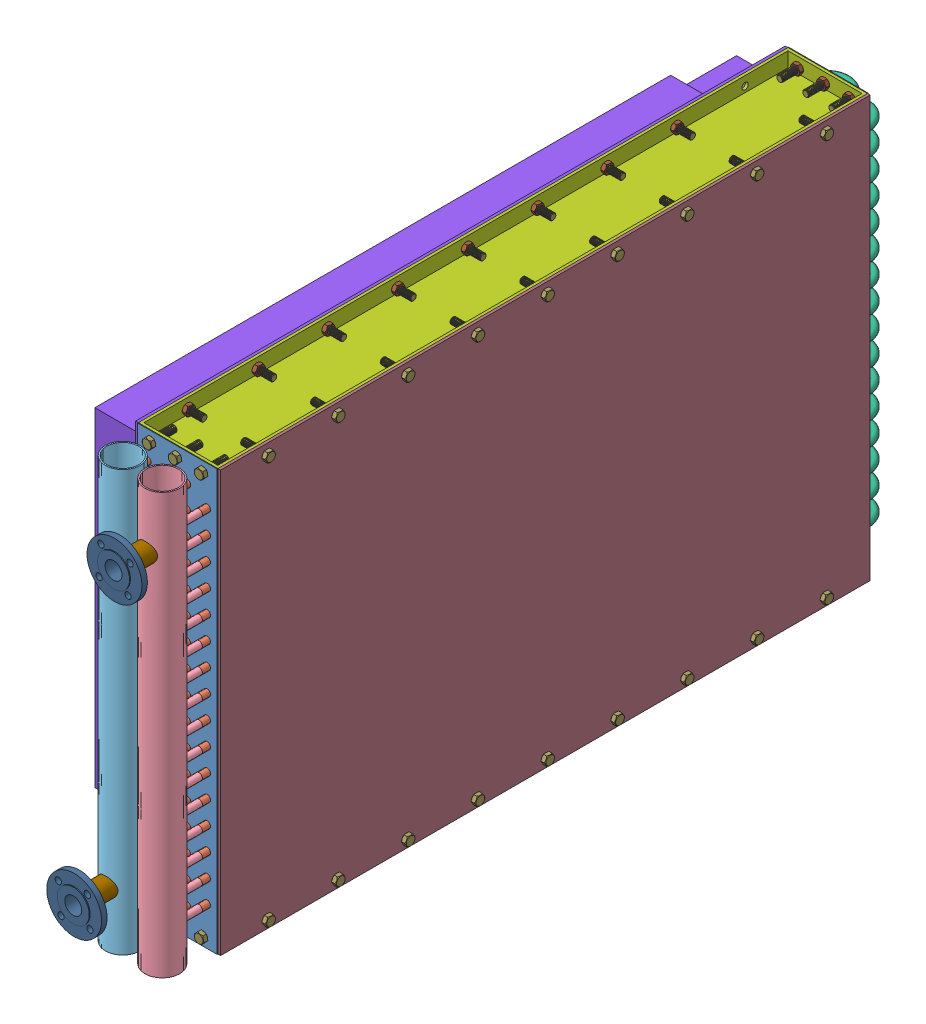
SolidWorks assembly Zagrijač zraka - assembly, configuration Default. Lengths in mm.
Overall size (396.33 920 1679.05).
277 component instances, 14 part files, 58 mates.
Components (placement in the parent):
- Početna i krajnja izmjenjivačka lamela - zagrijač zraka-2: Početna i krajnja izmjenjivačka lamela - zagrijač zraka [Default] at (252.8729 497.8938 741.12) size (173.9 920 1.5)
- Izmjenjivačka cijev - zagrijač zraka-2: Izmjenjivačka cijev - zagrijač zraka [Default] at (274.5217 897.8938 -699.63) x (0.942593 -0.333944 0) z (0 0 1) size (15 15 1460)
- Izmjenjivačka lamela - zagrijač zraka-2: Izmjenjivačka lamela - zagrijač zraka [Default] at (252.8729 497.8938 719.62) size (173.9 850 1.5)
- Izmjenjivačka lamela - zagrijač zraka-142: Izmjenjivačka lamela - zagrijač zraka [Default] at (252.8729 497.8938 699.62) size (173.9 850 1.5)
- Izmjenjivačka lamela - zagrijač zraka-143: Izmjenjivačka lamela - zagrijač zraka [Default] at (252.8729 497.8938 679.62) size (173.9 850 1.5)
- Izmjenjivačka lamela - zagrijač zraka-144: Izmjenjivačka lamela - zagrijač zraka [Default] at (252.8729 497.8938 659.62) size (173.9 850 1.5)
- Izmjenjivačka lamela - zagrijač zraka-145: Izmjenjivačka lamela - zagrijač zraka [Default] at (252.8729 497.8938 639.62) size (173.9 850 1.5)
- Izmjenjivačka lamela - zagrijač zraka-146: Izmjenjivačka lamela - zagrijač zraka [Default] at (252.8729 497.8938 619.62) size (173.9 850 1.5)
- Izmjenjivačka lamela - zagrijač zraka-147: Izmjenjivačka lamela - zagrijač zraka [Default] at (252.8729 497.8938 599.62) size (173.9 850 1.5)
- Izmjenjivačka lamela - zagrijač zraka-148: Izmjenjivačka lamela - zagrijač zraka [Default] at (252.8729 497.8938 579.62) size (173.9 850 1.5)
- Izmjenjivačka lamela - zagrijač zraka-149: Izmjenjivačka lamela - zagrijač zraka [Default] at (252.8729 497.8938 559.62) size (173.9 850 1.5)
- Izmjenjivačka lamela - zagrijač zraka-150: Izmjenjivačka lamela - zagrijač zraka [Default] at (252.8729 497.8938 539.62) size (173.9 850 1.5)
- Izmjenjivačka lamela - zagrijač zraka-151: Izmjenjivačka lamela - zagrijač zraka [Default] at (252.8729 497.8938 519.62) size (173.9 850 1.5)
- Izmjenjivačka lamela - zagrijač zraka-152: Izmjenjivačka lamela - zagrijač zraka [Default] at (252.8729 497.8938 499.62) size (173.9 850 1.5)
- Izmjenjivačka lamela - zagrijač zraka-153: Izmjenjivačka lamela - zagrijač zraka [Default] at (252.8729 497.8938 479.62) size (173.9 850 1.5)
- Izmjenjivačka lamela - zagrijač zraka-154: Izmjenjivačka lamela - zagrijač zraka [Default] at (252.8729 497.8938 459.62) size (173.9 850 1.5)
- Izmjenjivačka lamela - zagrijač zraka-155: Izmjenjivačka lamela - zagrijač zraka [Default] at (252.8729 497.8938 439.62) size (173.9 850 1.5)
- Izmjenjivačka lamela - zagrijač zraka-156: Izmjenjivačka lamela - zagrijač zraka [Default] at (252.8729 497.8938 419.62) size (173.9 850 1.5)
- Izmjenjivačka lamela - zagrijač zraka-157: Izmjenjivačka lamela - zagrijač zraka [Default] at (252.8729 497.8938 399.62) size (173.9 850 1.5)
- Izmjenjivačka lamela - zagrijač zraka-158: Izmjenjivačka lamela - zagrijač zraka [Default] at (252.8729 497.8938 379.62) size (173.9 850 1.5)
- Izmjenjivačka lamela - zagrijač zraka-159: Izmjenjivačka lamela - zagrijač zraka [Default] at (252.8729 497.8938 359.62) size (173.9 850 1.5)
- Izmjenjivačka lamela - zagrijač zraka-160: Izmjenjivačka lamela - zagrijač zraka [Default] at (252.8729 497.8938 339.62) size (173.9 850 1.5)
- Izmjenjivačka lamela - zagrijač zraka-161: Izmjenjivačka lamela - zagrijač zraka [Default] at (252.8729 497.8938 319.62) size (173.9 850 1.5)
- Izmjenjivačka lamela - zagrijač zraka-162: Izmjenjivačka lamela - zagrijač zraka [Default] at (252.8729 497.8938 299.62) size (173.9 850 1.5)
- Izmjenjivačka lamela - zagrijač zraka-163: Izmjenjivačka lamela - zagrijač zraka [Default] at (252.8729 497.8938 279.62) size (173.9 850 1.5)
- Izmjenjivačka lamela - zagrijač zraka-164: Izmjenjivačka lamela - zagrijač zraka [Default] at (252.8729 497.8938 259.62) size (173.9 850 1.5)
- Izmjenjivačka lamela - zagrijač zraka-165: Izmjenjivačka lamela - zagrijač zraka [Default] at (252.8729 497.8938 239.62) size (173.9 850 1.5)
- Izmjenjivačka lamela - zagrijač zraka-166: Izmjenjivačka lamela - zagrijač zraka [Default] at (252.8729 497.8938 219.62) size (173.9 850 1.5)
- Izmjenjivačka lamela - zagrijač zraka-167: Izmjenjivačka lamela - zagrijač zraka [Default] at (252.8729 497.8938 199.62) size (173.9 850 1.5)
- Izmjenjivačka lamela - zagrijač zraka-168: Izmjenjivačka lamela - zagrijač zraka [Default] at (252.8729 497.8938 179.62) size (173.9 850 1.5)
- Izmjenjivačka lamela - zagrijač zraka-169: Izmjenjivačka lamela - zagrijač zraka [Default] at (252.8729 497.8938 159.62) size (173.9 850 1.5)
- Izmjenjivačka lamela - zagrijač zraka-170: Izmjenjivačka lamela - zagrijač zraka [Default] at (252.8729 497.8938 139.62) size (173.9 850 1.5)
- Izmjenjivačka lamela - zagrijač zraka-171: Izmjenjivačka lamela - zagrijač zraka [Default] at (252.8729 497.8938 119.62) size (173.9 850 1.5)
- Izmjenjivačka lamela - zagrijač zraka-172: Izmjenjivačka lamela - zagrijač zraka [Default] at (252.8729 497.8938 99.62) size (173.9 850 1.5)
- Izmjenjivačka lamela - zagrijač zraka-173: Izmjenjivačka lamela - zagrijač zraka [Default] at (252.8729 497.8938 79.62) size (173.9 850 1.5)
- Izmjenjivačka lamela - zagrijač zraka-174: Izmjenjivačka lamela - zagrijač zraka [Default] at (252.8729 497.8938 59.62) size (173.9 850 1.5)
- Izmjenjivačka lamela - zagrijač zraka-175: Izmjenjivačka lamela - zagrijač zraka [Default] at (252.8729 497.8938 39.62) size (173.9 850 1.5)
- Izmjenjivačka lamela - zagrijač zraka-176: Izmjenjivačka lamela - zagrijač zraka [Default] at (252.8729 497.8938 19.62) size (173.9 850 1.5)
- Izmjenjivačka lamela - zagrijač zraka-177: Izmjenjivačka lamela - zagrijač zraka [Default] at (252.8729 497.8938 -0.38) size (173.9 850 1.5)
- Izmjenjivačka lamela - zagrijač zraka-178: Izmjenjivačka lamela - zagrijač zraka [Default] at (252.8729 497.8938 -20.38) size (173.9 850 1.5)
- Izmjenjivačka lamela - zagrijač zraka-179: Izmjenjivačka lamela - zagrijač zraka [Default] at (252.8729 497.8938 -40.38) size (173.9 850 1.5)
- Izmjenjivačka lamela - zagrijač zraka-180: Izmjenjivačka lamela - zagrijač zraka [Default] at (252.8729 497.8938 -60.38) size (173.9 850 1.5)
- Izmjenjivačka lamela - zagrijač zraka-181: Izmjenjivačka lamela - zagrijač zraka [Default] at (252.8729 497.8938 -80.38) size (173.9 850 1.5)
- Izmjenjivačka lamela - zagrijač zraka-182: Izmjenjivačka lamela - zagrijač zraka [Default] at (252.8729 497.8938 -100.38) size (173.9 850 1.5)
- Izmjenjivačka lamela - zagrijač zraka-183: Izmjenjivačka lamela - zagrijač zraka [Default] at (252.8729 497.8938 -120.38) size (173.9 850 1.5)
- Izmjenjivačka lamela - zagrijač zraka-184: Izmjenjivačka lamela - zagrijač zraka [Default] at (252.8729 497.8938 -140.38) size (173.9 850 1.5)
- Izmjenjivačka lamela - zagrijač zraka-185: Izmjenjivačka lamela - zagrijač zraka [Default] at (252.8729 497.8938 -160.38) size (173.9 850 1.5)
- Izmjenjivačka lamela - zagrijač zraka-186: Izmjenjivačka lamela - zagrijač zraka [Default] at (252.8729 497.8938 -180.38) size (173.9 850 1.5)
- Izmjenjivačka lamela - zagrijač zraka-187: Izmjenjivačka lamela - zagrijač zraka [Default] at (252.8729 497.8938 -200.38) size (173.9 850 1.5)
- Izmjenjivačka lamela - zagrijač zraka-188: Izmjenjivačka lamela - zagrijač zraka [Default] at (252.8729 497.8938 -220.38) size (173.9 850 1.5)
- Izmjenjivačka lamela - zagrijač zraka-189: Izmjenjivačka lamela - zagrijač zraka [Default] at (252.8729 497.8938 -240.38) size (173.9 850 1.5)
- Izmjenjivačka lamela - zagrijač zraka-190: Izmjenjivačka lamela - zagrijač zraka [Default] at (252.8729 497.8938 -260.38) size (173.9 850 1.5)
- Izmjenjivačka lamela - zagrijač zraka-191: Izmjenjivačka lamela - zagrijač zraka [Default] at (252.8729 497.8938 -280.38) size (173.9 850 1.5)
- Izmjenjivačka lamela - zagrijač zraka-192: Izmjenjivačka lamela - zagrijač zraka [Default] at (252.8729 497.8938 -300.38) size (173.9 850 1.5)
- Izmjenjivačka lamela - zagrijač zraka-193: Izmjenjivačka lamela - zagrijač zraka [Default] at (252.8729 497.8938 -320.38) size (173.9 850 1.5)
- Izmjenjivačka lamela - zagrijač zraka-194: Izmjenjivačka lamela - zagrijač zraka [Default] at (252.8729 497.8938 -340.38) size (173.9 850 1.5)
- Izmjenjivačka lamela - zagrijač zraka-195: Izmjenjivačka lamela - zagrijač zraka [Default] at (252.8729 497.8938 -360.38) size (173.9 850 1.5)
- Izmjenjivačka lamela - zagrijač zraka-196: Izmjenjivačka lamela - zagrijač zraka [Default] at (252.8729 497.8938 -380.38) size (173.9 850 1.5)
- Izmjenjivačka lamela - zagrijač zraka-197: Izmjenjivačka lamela - zagrijač zraka [Default] at (252.8729 497.8938 -400.38) size (173.9 850 1.5)
- Izmjenjivačka lamela - zagrijač zraka-198: Izmjenjivačka lamela - zagrijač zraka [Default] at (252.8729 497.8938 -420.38) size (173.9 850 1.5)
- Izmjenjivačka lamela - zagrijač zraka-199: Izmjenjivačka lamela - zagrijač zraka [Default] at (252.8729 497.8938 -440.38) size (173.9 850 1.5)
- Izmjenjivačka lamela - zagrijač zraka-200: Izmjenjivačka lamela - zagrijač zraka [Default] at (252.8729 497.8938 -460.38) size (173.9 850 1.5)
- Izmjenjivačka lamela - zagrijač zraka-201: Izmjenjivačka lamela - zagrijač zraka [Default] at (252.8729 497.8938 -480.38) size (173.9 850 1.5)
- Izmjenjivačka lamela - zagrijač zraka-202: Izmjenjivačka lamela - zagrijač zraka [Default] at (252.8729 497.8938 -500.38) size (173.9 850 1.5)
- Izmjenjivačka lamela - zagrijač zraka-203: Izmjenjivačka lamela - zagrijač zraka [Default] at (252.8729 497.8938 -520.38) size (173.9 850 1.5)
- Izmjenjivačka lamela - zagrijač zraka-204: Izmjenjivačka lamela - zagrijač zraka [Default] at (252.8729 497.8938 -540.38) size (173.9 850 1.5)
- Izmjenjivačka lamela - zagrijač zraka-205: Izmjenjivačka lamela - zagrijač zraka [Default] at (252.8729 497.8938 -560.38) size (173.9 850 1.5)
- Izmjenjivačka lamela - zagrijač zraka-206: Izmjenjivačka lamela - zagrijač zraka [Default] at (252.8729 497.8938 -580.38) size (173.9 850 1.5)
- Izmjenjivačka lamela - zagrijač zraka-207: Izmjenjivačka lamela - zagrijač zraka [Default] at (252.8729 497.8938 -600.38) size (173.9 850 1.5)
- Izmjenjivačka lamela - zagrijač zraka-208: Izmjenjivačka lamela - zagrijač zraka [Default] at (252.8729 497.8938 -620.38) size (173.9 850 1.5)
- Izmjenjivačka lamela - zagrijač zraka-209: Izmjenjivačka lamela - zagrijač zraka [Default] at (252.8729 497.8938 -640.38) size (173.9 850 1.5)
- Izmjenjivačka lamela - zagrijač zraka-210: Izmjenjivačka lamela - zagrijač zraka [Default] at (252.8729 497.8938 -660.38) size (173.9 850 1.5)
- Početna i krajnja izmjenjivačka lamela - zagrijač zraka-6: Početna i krajnja izmjenjivačka lamela - zagrijač zraka [Default] at (252.8729 497.8938 -681.88) size (173.9 920 1.5)
- Izmjenjivačka cijev - zagrijač zraka-3: Izmjenjivačka cijev - zagrijač zraka [Default] at (187.9217 897.8938 -699.63) x (0.942593 -0.333944 0) z (0 0 1) size (15 15 1460)
- Izmjenjivačka cijev - zagrijač zraka-4: Izmjenjivačka cijev - zagrijač zraka [Default] at (274.5217 847.8938 -699.63) x (0.942593 -0.333944 0) z (0 0 1) size (15 15 1460)
- Izmjenjivačka cijev - zagrijač zraka-5: Izmjenjivačka cijev - zagrijač zraka [Default] at (187.9217 847.8938 -699.63) x (0.942593 -0.333944 0) z (0 0 1) size (15 15 1460)
- Izmjenjivačka cijev - zagrijač zraka-6: Izmjenjivačka cijev - zagrijač zraka [Default] at (274.5217 797.8938 -699.63) x (0.942593 -0.333944 0) z (0 0 1) size (15 15 1460)
- Izmjenjivačka cijev - zagrijač zraka-7: Izmjenjivačka cijev - zagrijač zraka [Default] at (187.9217 797.8938 -699.63) x (0.942593 -0.333944 0) z (0 0 1) size (15 15 1460)
- Izmjenjivačka cijev - zagrijač zraka-8: Izmjenjivačka cijev - zagrijač zraka [Default] at (274.5217 747.8938 -699.63) x (0.942593 -0.333944 0) z (0 0 1) size (15 15 1460)
- Izmjenjivačka cijev - zagrijač zraka-9: Izmjenjivačka cijev - zagrijač zraka [Default] at (187.9217 747.8938 -699.63) x (0.942593 -0.333944 0) z (0 0 1) size (15 15 1460)
- Izmjenjivačka cijev - zagrijač zraka-10: Izmjenjivačka cijev - zagrijač zraka [Default] at (274.5217 697.8938 -699.63) x (0.942593 -0.333944 0) z (0 0 1) size (15 15 1460)
- Izmjenjivačka cijev - zagrijač zraka-11: Izmjenjivačka cijev - zagrijač zraka [Default] at (187.9217 697.8938 -699.63) x (0.942593 -0.333944 0) z (0 0 1) size (15 15 1460)
- Izmjenjivačka cijev - zagrijač zraka-12: Izmjenjivačka cijev - zagrijač zraka [Default] at (274.5217 647.8938 -699.63) x (0.942593 -0.333944 0) z (0 0 1) size (15 15 1460)
- Izmjenjivačka cijev - zagrijač zraka-13: Izmjenjivačka cijev - zagrijač zraka [Default] at (187.9217 647.8938 -699.63) x (0.942593 -0.333944 0) z (0 0 1) size (15 15 1460)
- Izmjenjivačka cijev - zagrijač zraka-14: Izmjenjivačka cijev - zagrijač zraka [Default] at (274.5217 597.8938 -699.63) x (0.942593 -0.333944 0) z (0 0 1) size (15 15 1460)
- Izmjenjivačka cijev - zagrijač zraka-15: Izmjenjivačka cijev - zagrijač zraka [Default] at (187.9217 597.8938 -699.63) x (0.942593 -0.333944 0) z (0 0 1) size (15 15 1460)
- Izmjenjivačka cijev - zagrijač zraka-16: Izmjenjivačka cijev - zagrijač zraka [Default] at (274.5217 547.8938 -699.63) x (0.942593 -0.333944 0) z (0 0 1) size (15 15 1460)
- Izmjenjivačka cijev - zagrijač zraka-17: Izmjenjivačka cijev - zagrijač zraka [Default] at (187.9217 547.8938 -699.63) x (0.942593 -0.333944 0) z (0 0 1) size (15 15 1460)
- Izmjenjivačka cijev - zagrijač zraka-18: Izmjenjivačka cijev - zagrijač zraka [Default] at (274.5217 497.8938 -699.63) x (0.942593 -0.333944 0) z (0 0 1) size (15 15 1460)
- Izmjenjivačka cijev - zagrijač zraka-19: Izmjenjivačka cijev - zagrijač zraka [Default] at (187.9217 497.8938 -699.63) x (0.942593 -0.333944 0) z (0 0 1) size (15 15 1460)
- Izmjenjivačka cijev - zagrijač zraka-20: Izmjenjivačka cijev - zagrijač zraka [Default] at (274.5217 447.8938 -699.63) x (0.942593 -0.333944 0) z (0 0 1) size (15 15 1460)
- Izmjenjivačka cijev - zagrijač zraka-21: Izmjenjivačka cijev - zagrijač zraka [Default] at (187.9217 447.8938 -699.63) x (0.942593 -0.333944 0) z (0 0 1) size (15 15 1460)
- Izmjenjivačka cijev - zagrijač zraka-22: Izmjenjivačka cijev - zagrijač zraka [Default] at (274.5217 397.8938 -699.63) x (0.942593 -0.333944 0) z (0 0 1) size (15 15 1460)
- Izmjenjivačka cijev - zagrijač zraka-23: Izmjenjivačka cijev - zagrijač zraka [Default] at (187.9217 397.8938 -699.63) x (0.942593 -0.333944 0) z (0 0 1) size (15 15 1460)
- Izmjenjivačka cijev - zagrijač zraka-24: Izmjenjivačka cijev - zagrijač zraka [Default] at (274.5217 347.8938 -699.63) x (0.942593 -0.333944 0) z (0 0 1) size (15 15 1460)
- Izmjenjivačka cijev - zagrijač zraka-25: Izmjenjivačka cijev - zagrijač zraka [Default] at (187.9217 347.8938 -699.63) x (0.942593 -0.333944 0) z (0 0 1) size (15 15 1460)
- Izmjenjivačka cijev - zagrijač zraka-26: Izmjenjivačka cijev - zagrijač zraka [Default] at (274.5217 297.8938 -699.63) x (0.942593 -0.333944 0) z (0 0 1) size (15 15 1460)
- Izmjenjivačka cijev - zagrijač zraka-27: Izmjenjivačka cijev - zagrijač zraka [Default] at (187.9217 297.8938 -699.63) x (0.942593 -0.333944 0) z (0 0 1) size (15 15 1460)
- Izmjenjivačka cijev - zagrijač zraka-28: Izmjenjivačka cijev - zagrijač zraka [Default] at (274.5217 247.8938 -699.63) x (0.942593 -0.333944 0) z (0 0 1) size (15 15 1460)
- Izmjenjivačka cijev - zagrijač zraka-29: Izmjenjivačka cijev - zagrijač zraka [Default] at (187.9217 247.8938 -699.63) x (0.942593 -0.333944 0) z (0 0 1) size (15 15 1460)
- Izmjenjivačka cijev - zagrijač zraka-30: Izmjenjivačka cijev - zagrijač zraka [Default] at (274.5217 197.8938 -699.63) x (0.942593 -0.333944 0) z (0 0 1) size (15 15 1460)
- Izmjenjivačka cijev - zagrijač zraka-31: Izmjenjivačka cijev - zagrijač zraka [Default] at (187.9217 197.8938 -699.63) x (0.942593 -0.333944 0) z (0 0 1) size (15 15 1460)
- Izmjenjivačka cijev - zagrijač zraka-32: Izmjenjivačka cijev - zagrijač zraka [Default] at (274.5217 147.8938 -699.63) x (0.942593 -0.333944 0) z (0 0 1) size (15 15 1460)
- Izmjenjivačka cijev - zagrijač zraka-33: Izmjenjivačka cijev - zagrijač zraka [Default] at (187.9217 147.8938 -699.63) x (0.942593 -0.333944 0) z (0 0 1) size (15 15 1460)
- Izmjenjivačka cijev - zagrijač zraka-34: Izmjenjivačka cijev - zagrijač zraka [Default] at (274.5217 97.8938 -699.63) x (0.942593 -0.333944 0) z (0 0 1) size (15 15 1460)
- Izmjenjivačka cijev - zagrijač zraka-35: Izmjenjivačka cijev - zagrijač zraka [Default] at (187.9217 97.8938 -699.63) x (0.942593 -0.333944 0) z (0 0 1) size (15 15 1460)
- Izmjenjivačka cijev - zagrijač zraka-36: Izmjenjivačka cijev - zagrijač zraka [Default] at (317.8229 872.8938 -699.63) size (15 15 1460)
- Izmjenjivačka cijev - zagrijač zraka-37: Izmjenjivačka cijev - zagrijač zraka [Default] at (317.8229 822.8938 -699.63) size (15 15 1460)
- Izmjenjivačka cijev - zagrijač zraka-38: Izmjenjivačka cijev - zagrijač zraka [Default] at (317.8229 772.8938 -699.63) size (15 15 1460)
- Izmjenjivačka cijev - zagrijač zraka-39: Izmjenjivačka cijev - zagrijač zraka [Default] at (317.8229 722.8938 -699.63) size (15 15 1460)
- Izmjenjivačka cijev - zagrijač zraka-40: Izmjenjivačka cijev - zagrijač zraka [Default] at (317.8229 672.8938 -699.63) size (15 15 1460)
- Izmjenjivačka cijev - zagrijač zraka-41: Izmjenjivačka cijev - zagrijač zraka [Default] at (317.8229 622.8938 -699.63) size (15 15 1460)
- Izmjenjivačka cijev - zagrijač zraka-42: Izmjenjivačka cijev - zagrijač zraka [Default] at (317.8229 572.8938 -699.63) size (15 15 1460)
- Izmjenjivačka cijev - zagrijač zraka-43: Izmjenjivačka cijev - zagrijač zraka [Default] at (317.8229 522.8938 -699.63) size (15 15 1460)
- Izmjenjivačka cijev - zagrijač zraka-44: Izmjenjivačka cijev - zagrijač zraka [Default] at (317.8229 472.8938 -699.63) size (15 15 1460)
- Izmjenjivačka cijev - zagrijač zraka-45: Izmjenjivačka cijev - zagrijač zraka [Default] at (317.8229 422.8938 -699.63) size (15 15 1460)
- Izmjenjivačka cijev - zagrijač zraka-46: Izmjenjivačka cijev - zagrijač zraka [Default] at (317.8229 372.8938 -699.63) size (15 15 1460)
- Izmjenjivačka cijev - zagrijač zraka-47: Izmjenjivačka cijev - zagrijač zraka [Default] at (317.8229 322.8938 -699.63) size (15 15 1460)
- Izmjenjivačka cijev - zagrijač zraka-48: Izmjenjivačka cijev - zagrijač zraka [Default] at (317.8229 272.8938 -699.63) size (15 15 1460)
- Izmjenjivačka cijev - zagrijač zraka-49: Izmjenjivačka cijev - zagrijač zraka [Default] at (317.8229 222.8938 -699.63) size (15 15 1460)
- Izmjenjivačka cijev - zagrijač zraka-50: Izmjenjivačka cijev - zagrijač zraka [Default] at (317.8229 172.8938 -699.63) size (15 15 1460)
- Izmjenjivačka cijev - zagrijač zraka-51: Izmjenjivačka cijev - zagrijač zraka [Default] at (317.8229 122.8938 -699.63) size (15 15 1460)
- Izmjenjivačka cijev - zagrijač zraka-52: Izmjenjivačka cijev - zagrijač zraka [Default] at (231.2229 872.8938 -699.63) size (15 15 1460)
- Izmjenjivačka cijev - zagrijač zraka-53: Izmjenjivačka cijev - zagrijač zraka [Default] at (231.2229 822.8938 -699.63) size (15 15 1460)
- Izmjenjivačka cijev - zagrijač zraka-54: Izmjenjivačka cijev - zagrijač zraka [Default] at (231.2229 772.8938 -699.63) size (15 15 1460)
- Izmjenjivačka cijev - zagrijač zraka-55: Izmjenjivačka cijev - zagrijač zraka [Default] at (231.2229 722.8938 -699.63) size (15 15 1460)
- Izmjenjivačka cijev - zagrijač zraka-56: Izmjenjivačka cijev - zagrijač zraka [Default] at (231.2229 672.8938 -699.63) size (15 15 1460)
- Izmjenjivačka cijev - zagrijač zraka-57: Izmjenjivačka cijev - zagrijač zraka [Default] at (231.2229 622.8938 -699.63) size (15 15 1460)
- Izmjenjivačka cijev - zagrijač zraka-58: Izmjenjivačka cijev - zagrijač zraka [Default] at (231.2229 572.8938 -699.63) size (15 15 1460)
- Izmjenjivačka cijev - zagrijač zraka-59: Izmjenjivačka cijev - zagrijač zraka [Default] at (231.2229 522.8938 -699.63) size (15 15 1460)
- Izmjenjivačka cijev - zagrijač zraka-60: Izmjenjivačka cijev - zagrijač zraka [Default] at (231.2229 472.8938 -699.63) size (15 15 1460)
- Izmjenjivačka cijev - zagrijač zraka-61: Izmjenjivačka cijev - zagrijač zraka [Default] at (231.2229 422.8938 -699.63) size (15 15 1460)
- Izmjenjivačka cijev - zagrijač zraka-62: Izmjenjivačka cijev - zagrijač zraka [Default] at (231.2229 372.8938 -699.63) size (15 15 1460)
- Izmjenjivačka cijev - zagrijač zraka-63: Izmjenjivačka cijev - zagrijač zraka [Default] at (231.2229 322.8938 -699.63) size (15 15 1460)
- Izmjenjivačka cijev - zagrijač zraka-64: Izmjenjivačka cijev - zagrijač zraka [Default] at (231.2229 272.8938 -699.63) size (15 15 1460)
- Izmjenjivačka cijev - zagrijač zraka-65: Izmjenjivačka cijev - zagrijač zraka [Default] at (231.2229 222.8938 -699.63) size (15 15 1460)
- Izmjenjivačka cijev - zagrijač zraka-66: Izmjenjivačka cijev - zagrijač zraka [Default] at (231.2229 172.8938 -699.63) size (15 15 1460)
- Izmjenjivačka cijev - zagrijač zraka-67: Izmjenjivačka cijev - zagrijač zraka [Default] at (231.2229 122.8938 -699.63) size (15 15 1460)
- Ulazni kolektor - zagrijač zraka-1: Ulazni kolektor - zagrijač zraka [Default] at (297.5717 37.8938 820.37) x (-1 0 0) z (0 0 -1) size (76.1 920 98.05)
- Izlazni kolektor - zagrijač zraka-1: Izlazni kolektor - zagrijač zraka [Default] at (210.9717 37.8938 820.3712) x (-1 0 0) z (0 0 -1) size (76.1 920 98.05)
- U-spojnica - zagrijač zraka-1: U-spojnica - zagrijač zraka [Default] at (187.9217 897.8938 -699.63) x (1 0 0) z (0 1 0) size (101.6 50.8 15)
- U-spojnica - zagrijač zraka-2: U-spojnica - zagrijač zraka [Default] at (187.9217 847.8938 -699.63) x (1 0 0) z (0 1 0) size (101.6 50.8 15)
- U-spojnica - zagrijač zraka-3: U-spojnica - zagrijač zraka [Default] at (187.9217 797.8938 -699.63) x (1 0 0) z (0 1 0) size (101.6 50.8 15)
- U-spojnica - zagrijač zraka-4: U-spojnica - zagrijač zraka [Default] at (187.9217 747.8938 -699.63) x (1 0 0) z (0 1 0) size (101.6 50.8 15)
- U-spojnica - zagrijač zraka-5: U-spojnica - zagrijač zraka [Default] at (187.9217 697.8938 -699.63) x (1 0 0) z (0 1 0) size (101.6 50.8 15)
- U-spojnica - zagrijač zraka-6: U-spojnica - zagrijač zraka [Default] at (187.9217 647.8938 -699.63) x (1 0 0) z (0 1 0) size (101.6 50.8 15)
- U-spojnica - zagrijač zraka-7: U-spojnica - zagrijač zraka [Default] at (187.9217 597.8938 -699.63) x (1 0 0) z (0 1 0) size (101.6 50.8 15)
- U-spojnica - zagrijač zraka-8: U-spojnica - zagrijač zraka [Default] at (187.9217 547.8938 -699.63) x (1 0 0) z (0 1 0) size (101.6 50.8 15)
- U-spojnica - zagrijač zraka-9: U-spojnica - zagrijač zraka [Default] at (187.9217 497.8938 -699.63) x (1 0 0) z (0 1 0) size (101.6 50.8 15)
- U-spojnica - zagrijač zraka-10: U-spojnica - zagrijač zraka [Default] at (187.9217 447.8938 -699.63) x (1 0 0) z (0 1 0) size (101.6 50.8 15)
- U-spojnica - zagrijač zraka-11: U-spojnica - zagrijač zraka [Default] at (187.9217 397.8938 -699.63) x (1 0 0) z (0 1 0) size (101.6 50.8 15)
- U-spojnica - zagrijač zraka-12: U-spojnica - zagrijač zraka [Default] at (187.9217 347.8938 -699.63) x (1 0 0) z (0 1 0) size (101.6 50.8 15)
- U-spojnica - zagrijač zraka-13: U-spojnica - zagrijač zraka [Default] at (187.9217 297.8938 -699.63) x (1 0 0) z (0 1 0) size (101.6 50.8 15)
- U-spojnica - zagrijač zraka-14: U-spojnica - zagrijač zraka [Default] at (187.9217 247.8938 -699.63) x (1 0 0) z (0 1 0) size (101.6 50.8 15)
- U-spojnica - zagrijač zraka-15: U-spojnica - zagrijač zraka [Default] at (187.9217 197.8938 -699.63) x (1 0 0) z (0 1 0) size (101.6 50.8 15)
- U-spojnica - zagrijač zraka-16: U-spojnica - zagrijač zraka [Default] at (187.9217 147.8938 -699.63) x (1 0 0) z (0 1 0) size (101.6 50.8 15)
- U-spojnica - zagrijač zraka-17: U-spojnica - zagrijač zraka [Default] at (187.9217 97.8938 -699.63) x (1 0 0) z (0 1 0) size (101.6 50.8 15)
- U-spojnica - zagrijač zraka-18: U-spojnica - zagrijač zraka [Default] at (231.2229 872.8938 -699.63) x (1 0 0) z (0 1 0) size (101.6 50.8 15)
- U-spojnica - zagrijač zraka-19: U-spojnica - zagrijač zraka [Default] at (231.2229 822.8938 -699.63) x (1 0 0) z (0 1 0) size (101.6 50.8 15)
- U-spojnica - zagrijač zraka-20: U-spojnica - zagrijač zraka [Default] at (231.2229 772.8938 -699.63) x (1 0 0) z (0 1 0) size (101.6 50.8 15)
- U-spojnica - zagrijač zraka-21: U-spojnica - zagrijač zraka [Default] at (231.2229 722.8938 -699.63) x (1 0 0) z (0 1 0) size (101.6 50.8 15)
- U-spojnica - zagrijač zraka-22: U-spojnica - zagrijač zraka [Default] at (231.2229 672.8938 -699.63) x (1 0 0) z (0 1 0) size (101.6 50.8 15)
- U-spojnica - zagrijač zraka-23: U-spojnica - zagrijač zraka [Default] at (231.2229 622.8938 -699.63) x (1 0 0) z (0 1 0) size (101.6 50.8 15)
- U-spojnica - zagrijač zraka-24: U-spojnica - zagrijač zraka [Default] at (231.2229 572.8938 -699.63) x (1 0 0) z (0 1 0) size (101.6 50.8 15)
- U-spojnica - zagrijač zraka-25: U-spojnica - zagrijač zraka [Default] at (231.2229 522.8938 -699.63) x (1 0 0) z (0 1 0) size (101.6 50.8 15)
- U-spojnica - zagrijač zraka-26: U-spojnica - zagrijač zraka [Default] at (231.2229 472.8938 -699.63) x (1 0 0) z (0 1 0) size (101.6 50.8 15)
- U-spojnica - zagrijač zraka-27: U-spojnica - zagrijač zraka [Default] at (231.2229 422.8938 -699.63) x (1 0 0) z (0 1 0) size (101.6 50.8 15)
- U-spojnica - zagrijač zraka-28: U-spojnica - zagrijač zraka [Default] at (231.2229 372.8938 -699.63) x (1 0 0) z (0 1 0) size (101.6 50.8 15)
- U-spojnica - zagrijač zraka-29: U-spojnica - zagrijač zraka [Default] at (231.2229 322.8938 -699.63) x (1 0 0) z (0 1 0) size (101.6 50.8 15)
- U-spojnica - zagrijač zraka-30: U-spojnica - zagrijač zraka [Default] at (231.2229 272.8938 -699.63) x (1 0 0) z (0 1 0) size (101.6 50.8 15)
- U-spojnica - zagrijač zraka-31: U-spojnica - zagrijač zraka [Default] at (231.2229 222.8938 -699.63) x (1 0 0) z (0 1 0) size (101.6 50.8 15)
- U-spojnica - zagrijač zraka-32: U-spojnica - zagrijač zraka [Default] at (231.2229 172.8938 -699.63) x (1 0 0) z (0 1 0) size (101.6 50.8 15)
- U-spojnica - zagrijač zraka-33: U-spojnica - zagrijač zraka [Default] at (231.2229 122.8938 -699.63) x (1 0 0) z (0 1 0) size (101.6 50.8 15)
- Pokrovna stijenka - zagrijač zraka-1: Pokrovna stijenka - zagrijač zraka [Default] at (252.8729 957.8938 30.37) x (0 0 1) z (1 0 0) size (1421.5 35 173.9)
- Pokrovna stijenka - zagrijač zraka-2: Pokrovna stijenka - zagrijač zraka [Default] at (252.8729 37.8938 30.37) x (0 0 -1) z (1 0 0) size (1421.5 35 173.9)
- Kućište sa ventilatorom - zagrijač zraka-1: Kućište sa ventilatorom - zagrijač zraka [Default] at (165.9229 497.8938 30.37) x (0 0 -1) z (-1 0 0) size (1470.75 920 180)
- Priključna cijev - zagrijač zraka-1: Priključna cijev - zagrijač zraka [Default] at (297.5717 836.6938 832.0365) size (42.4 42.4 60)
- Priključna cijev - zagrijač zraka-2: Priključna cijev - zagrijač zraka [Default] at (210.9717 159.0938 833.6194) size (42.4 42.4 60)
- Prirubnica - zagrijač zraka-1: Prirubnica - zagrijač zraka [Default] at (297.5717 836.6938 927.0365) x (0.660561 -0.750772 0) z (0.750772 0.660561 0) size (120 35 120)
- Prirubnica - zagrijač zraka-2: Prirubnica - zagrijač zraka [Default] at (210.9717 159.0938 928.6194) x (0.769626 -0.638495 0) z (0.638495 0.769626 0) size (120 35 120)
- Matica - zagrijač zraka-1: Matica - zagrijač zraka [Default] at (309.8229 57.8938 726.12) size (25.38 22.75 9.17)
- Vijak - zagrijač zraka-1: Vijak - zagrijač zraka [Default] at (309.8229 57.8938 753.12) x (-0.684186 -0.729307 0) z (0 0 -1) size (25.4 22.36 60.5)
- Matica - zagrijač zraka-2: Matica - zagrijač zraka [Default] at (309.8229 937.8938 726.12) size (25.38 22.75 9.17)
- Matica - zagrijač zraka-3: Matica - zagrijač zraka [Default] at (252.8729 57.8938 726.12) size (25.38 22.75 9.17)
- Matica - zagrijač zraka-4: Matica - zagrijač zraka [Default] at (252.8729 937.8938 726.12) size (25.38 22.75 9.17)
- Matica - zagrijač zraka-5: Matica - zagrijač zraka [Default] at (195.9229 57.8938 726.12) size (25.38 22.75 9.17)
- Matica - zagrijač zraka-6: Matica - zagrijač zraka [Default] at (195.9229 937.8938 726.12) size (25.38 22.75 9.17)
- Vijak - zagrijač zraka-2: Vijak - zagrijač zraka [Default] at (309.8229 937.8938 753.12) x (-0.684186 -0.729307 0) z (0 0 -1) size (25.4 22.36 60.5)
- Vijak - zagrijač zraka-3: Vijak - zagrijač zraka [Default] at (252.8729 57.8938 753.12) x (-0.684186 -0.729307 0) z (0 0 -1) size (25.4 22.36 60.5)
- Vijak - zagrijač zraka-4: Vijak - zagrijač zraka [Default] at (252.8729 937.8938 753.12) x (-0.684186 -0.729307 0) z (0 0 -1) size (25.4 22.36 60.5)
- Vijak - zagrijač zraka-5: Vijak - zagrijač zraka [Default] at (195.9229 57.8938 753.12) x (-0.684186 -0.729307 0) z (0 0 -1) size (25.4 22.36 60.5)
- Vijak - zagrijač zraka-6: Vijak - zagrijač zraka [Default] at (195.9229 937.8938 753.12) x (-0.684186 -0.729307 0) z (0 0 -1) size (25.4 22.36 60.5)
- Zadnja strana - zagrijač zraka-1: Zadnja strana - zagrijač zraka [Default] at (339.8229 497.8938 30.37) x (0 0 -1) z (1 0 0) size (1421.5 920 6)
- Matica - zagrijač zraka-7: Matica - zagrijač zraka [Default] at (324.8229 57.8938 641.12) x (0 0 -1) z (1 0 0) size (25.38 22.75 9.17)
- Vijak - zagrijač zraka-7: Vijak - zagrijač zraka [Default] at (356.3229 57.8938 641.12) x (0 0 1) z (-1 0 0) size (25.4 22.36 60.5)
- Matica - zagrijač zraka-8: Matica - zagrijač zraka [Default] at (324.8229 937.8938 641.12) x (0 0 -1) z (1 0 0) size (25.38 22.75 9.17)
- Matica - zagrijač zraka-9: Matica - zagrijač zraka [Default] at (324.8229 57.8938 488.4325) x (0 0 -1) z (1 0 0) size (25.38 22.75 9.17)
- Matica - zagrijač zraka-10: Matica - zagrijač zraka [Default] at (324.8229 937.8938 488.4325) x (0 0 -1) z (1 0 0) size (25.38 22.75 9.17)
- Matica - zagrijač zraka-11: Matica - zagrijač zraka [Default] at (324.8229 57.8938 335.745) x (0 0 -1) z (1 0 0) size (25.38 22.75 9.17)
- Matica - zagrijač zraka-12: Matica - zagrijač zraka [Default] at (324.8229 937.8938 335.745) x (0 0 -1) z (1 0 0) size (25.38 22.75 9.17)
- Matica - zagrijač zraka-13: Matica - zagrijač zraka [Default] at (324.8229 57.8938 183.0575) x (0 0 -1) z (1 0 0) size (25.38 22.75 9.17)
- Matica - zagrijač zraka-14: Matica - zagrijač zraka [Default] at (324.8229 937.8938 183.0575) x (0 0 -1) z (1 0 0) size (25.38 22.75 9.17)
- Matica - zagrijač zraka-15: Matica - zagrijač zraka [Default] at (324.8229 57.8938 30.37) x (0 0 -1) z (1 0 0) size (25.38 22.75 9.17)
- Matica - zagrijač zraka-16: Matica - zagrijač zraka [Default] at (324.8229 937.8938 30.37) x (0 0 -1) z (1 0 0) size (25.38 22.75 9.17)
- Matica - zagrijač zraka-17: Matica - zagrijač zraka [Default] at (324.8229 57.8938 -122.3175) x (0 0 -1) z (1 0 0) size (25.38 22.75 9.17)
- Matica - zagrijač zraka-18: Matica - zagrijač zraka [Default] at (324.8229 937.8938 -122.3175) x (0 0 -1) z (1 0 0) size (25.38 22.75 9.17)
- Matica - zagrijač zraka-19: Matica - zagrijač zraka [Default] at (324.8229 57.8938 -275.005) x (0 0 -1) z (1 0 0) size (25.38 22.75 9.17)
- Matica - zagrijač zraka-20: Matica - zagrijač zraka [Default] at (324.8229 937.8938 -275.005) x (0 0 -1) z (1 0 0) size (25.38 22.75 9.17)
- Matica - zagrijač zraka-21: Matica - zagrijač zraka [Default] at (324.8229 57.8938 -427.6925) x (0 0 -1) z (1 0 0) size (25.38 22.75 9.17)
- Matica - zagrijač zraka-22: Matica - zagrijač zraka [Default] at (324.8229 937.8938 -427.6925) x (0 0 -1) z (1 0 0) size (25.38 22.75 9.17)
- Vijak - zagrijač zraka-8: Vijak - zagrijač zraka [Default] at (356.3229 937.8938 641.12) x (0 0 1) z (-1 0 0) size (25.4 22.36 60.5)
- Vijak - zagrijač zraka-9: Vijak - zagrijač zraka [Default] at (356.3229 57.8938 488.4325) x (0 0 1) z (-1 0 0) size (25.4 22.36 60.5)
- Vijak - zagrijač zraka-10: Vijak - zagrijač zraka [Default] at (356.3229 937.8938 488.4325) x (0 0 1) z (-1 0 0) size (25.4 22.36 60.5)
- Vijak - zagrijač zraka-11: Vijak - zagrijač zraka [Default] at (356.3229 57.8938 335.745) x (0 0 1) z (-1 0 0) size (25.4 22.36 60.5)
- Vijak - zagrijač zraka-12: Vijak - zagrijač zraka [Default] at (356.3229 937.8938 335.745) x (0 0 1) z (-1 0 0) size (25.4 22.36 60.5)
- Vijak - zagrijač zraka-13: Vijak - zagrijač zraka [Default] at (356.3229 57.8938 183.0575) x (0 0 1) z (-1 0 0) size (25.4 22.36 60.5)
- Vijak - zagrijač zraka-14: Vijak - zagrijač zraka [Default] at (356.3229 937.8938 183.0575) x (0 0 1) z (-1 0 0) size (25.4 22.36 60.5)
- Vijak - zagrijač zraka-15: Vijak - zagrijač zraka [Default] at (356.3229 57.8938 30.37) x (0 0 1) z (-1 0 0) size (25.4 22.36 60.5)
- Vijak - zagrijač zraka-16: Vijak - zagrijač zraka [Default] at (356.3229 937.8938 30.37) x (0 0 1) z (-1 0 0) size (25.4 22.36 60.5)
- Vijak - zagrijač zraka-17: Vijak - zagrijač zraka [Default] at (356.3229 57.8938 -122.3175) x (0 0 1) z (-1 0 0) size (25.4 22.36 60.5)
- Vijak - zagrijač zraka-18: Vijak - zagrijač zraka [Default] at (356.3229 937.8938 -122.3175) x (0 0 1) z (-1 0 0) size (25.4 22.36 60.5)
- Vijak - zagrijač zraka-19: Vijak - zagrijač zraka [Default] at (356.3229 57.8938 -275.005) x (0 0 1) z (-1 0 0) size (25.4 22.36 60.5)
- Vijak - zagrijač zraka-20: Vijak - zagrijač zraka [Default] at (356.3229 937.8938 -275.005) x (0 0 1) z (-1 0 0) size (25.4 22.36 60.5)
- Vijak - zagrijač zraka-21: Vijak - zagrijač zraka [Default] at (356.3229 57.8938 -427.6925) x (0 0 1) z (-1 0 0) size (25.4 22.36 60.5)
- Vijak - zagrijač zraka-22: Vijak - zagrijač zraka [Default] at (356.3229 937.8938 -427.6925) x (0 0 1) z (-1 0 0) size (25.4 22.36 60.5)
- Matica - zagrijač zraka-23: Matica - zagrijač zraka [Default] at (324.8229 57.8938 -580.38) x (0 0 -1) z (1 0 0) size (25.38 22.75 9.17)
- Vijak - zagrijač zraka-23: Vijak - zagrijač zraka [Default] at (356.3229 57.8938 -580.38) x (0 0 1) z (-1 0 0) size (25.4 22.36 60.5)
- Matica - zagrijač zraka-24: Matica - zagrijač zraka [Default] at (324.8229 937.8938 -580.38) x (0 0 -1) z (1 0 0) size (25.38 22.75 9.17)
- Vijak - zagrijač zraka-24: Vijak - zagrijač zraka [Default] at (356.3229 937.8938 -580.38) x (0 0 1) z (-1 0 0) size (25.4 22.36 60.5)
- Matica - zagrijač zraka-25: Matica - zagrijač zraka [Default] at (180.9229 57.8938 641.12) x (0 0 1) z (-1 0 0) size (25.38 22.75 9.17)
- Vijak - zagrijač zraka-25: Vijak - zagrijač zraka [Default] at (149.4229 57.8938 641.12) x (0 0 -1) z (1 0 0) size (25.4 22.36 60.5)
- Vijak - zagrijač zraka-26: Vijak - zagrijač zraka [Default] at (149.4229 57.8938 -580.38) x (0 0 -1) z (1 0 0) size (25.4 22.36 60.5)
- Matica - zagrijač zraka-26: Matica - zagrijač zraka [Default] at (180.9229 57.8938 -580.38) x (0 0 1) z (-1 0 0) size (25.38 22.75 9.17)
- Vijak - zagrijač zraka-27: Vijak - zagrijač zraka [Default] at (195.9229 57.8938 -692.38) size (25.4 22.36 60.5)
- Matica - zagrijač zraka-27: Matica - zagrijač zraka [Default] at (195.9229 57.8938 -674.38) size (25.38 22.75 9.17)
- Matica - zagrijač zraka-28: Matica - zagrijač zraka [Default] at (180.9229 57.8938 488.4325) x (0 0 1) z (-1 0 0) size (25.38 22.75 9.17)
- Matica - zagrijač zraka-29: Matica - zagrijač zraka [Default] at (180.9229 57.8938 335.745) x (0 0 1) z (-1 0 0) size (25.38 22.75 9.17)
- Matica - zagrijač zraka-30: Matica - zagrijač zraka [Default] at (180.9229 57.8938 183.0575) x (0 0 1) z (-1 0 0) size (25.38 22.75 9.17)
- Matica - zagrijač zraka-31: Matica - zagrijač zraka [Default] at (180.9229 57.8938 30.37) x (0 0 1) z (-1 0 0) size (25.38 22.75 9.17)
- Matica - zagrijač zraka-32: Matica - zagrijač zraka [Default] at (180.9229 57.8938 -122.3175) x (0 0 1) z (-1 0 0) size (25.38 22.75 9.17)
- Matica - zagrijač zraka-33: Matica - zagrijač zraka [Default] at (180.9229 57.8938 -275.005) x (0 0 1) z (-1 0 0) size (25.38 22.75 9.17)
- Matica - zagrijač zraka-34: Matica - zagrijač zraka [Default] at (180.9229 57.8938 -427.6925) x (0 0 1) z (-1 0 0) size (25.38 22.75 9.17)
- Matica - zagrijač zraka-35: Matica - zagrijač zraka [Default] at (180.9229 937.8938 641.12) x (0 0 1) z (-1 0 0) size (25.38 22.75 9.17)
- Matica - zagrijač zraka-36: Matica - zagrijač zraka [Default] at (180.9229 937.8938 488.4325) x (0 0 1) z (-1 0 0) size (25.38 22.75 9.17)
- Matica - zagrijač zraka-37: Matica - zagrijač zraka [Default] at (180.9229 937.8938 335.745) x (0 0 1) z (-1 0 0) size (25.38 22.75 9.17)
- Matica - zagrijač zraka-38: Matica - zagrijač zraka [Default] at (180.9229 937.8938 183.0575) x (0 0 1) z (-1 0 0) size (25.38 22.75 9.17)
- Matica - zagrijač zraka-39: Matica - zagrijač zraka [Default] at (180.9229 937.8938 30.37) x (0 0 1) z (-1 0 0) size (25.38 22.75 9.17)
- Matica - zagrijač zraka-40: Matica - zagrijač zraka [Default] at (180.9229 937.8938 -122.3175) x (0 0 1) z (-1 0 0) size (25.38 22.75 9.17)
- Matica - zagrijač zraka-41: Matica - zagrijač zraka [Default] at (180.9229 937.8938 -275.005) x (0 0 1) z (-1 0 0) size (25.38 22.75 9.17)
- Matica - zagrijač zraka-42: Matica - zagrijač zraka [Default] at (180.9229 937.8938 -427.6925) x (0 0 1) z (-1 0 0) size (25.38 22.75 9.17)
- Vijak - zagrijač zraka-28: Vijak - zagrijač zraka [Default] at (149.4229 57.8938 488.4325) x (0 0 -1) z (1 0 0) size (25.4 22.36 60.5)
- Vijak - zagrijač zraka-29: Vijak - zagrijač zraka [Default] at (149.4229 57.8938 335.745) x (0 0 -1) z (1 0 0) size (25.4 22.36 60.5)
- Vijak - zagrijač zraka-30: Vijak - zagrijač zraka [Default] at (149.4229 57.8938 183.0575) x (0 0 -1) z (1 0 0) size (25.4 22.36 60.5)
- Vijak - zagrijač zraka-31: Vijak - zagrijač zraka [Default] at (149.4229 57.8938 30.37) x (0 0 -1) z (1 0 0) size (25.4 22.36 60.5)
- Vijak - zagrijač zraka-32: Vijak - zagrijač zraka [Default] at (149.4229 57.8938 -122.3175) x (0 0 -1) z (1 0 0) size (25.4 22.36 60.5)
- Vijak - zagrijač zraka-33: Vijak - zagrijač zraka [Default] at (149.4229 57.8938 -275.005) x (0 0 -1) z (1 0 0) size (25.4 22.36 60.5)
- Vijak - zagrijač zraka-34: Vijak - zagrijač zraka [Default] at (149.4229 57.8938 -427.6925) x (0 0 -1) z (1 0 0) size (25.4 22.36 60.5)
- Vijak - zagrijač zraka-35: Vijak - zagrijač zraka [Default] at (149.4229 937.8938 641.12) x (0 0 -1) z (1 0 0) size (25.4 22.36 60.5)
- Vijak - zagrijač zraka-36: Vijak - zagrijač zraka [Default] at (149.4229 937.8938 488.4325) x (0 0 -1) z (1 0 0) size (25.4 22.36 60.5)
- Vijak - zagrijač zraka-37: Vijak - zagrijač zraka [Default] at (149.4229 937.8938 335.745) x (0 0 -1) z (1 0 0) size (25.4 22.36 60.5)
- Vijak - zagrijač zraka-38: Vijak - zagrijač zraka [Default] at (149.4229 937.8938 183.0575) x (0 0 -1) z (1 0 0) size (25.4 22.36 60.5)
- Vijak - zagrijač zraka-39: Vijak - zagrijač zraka [Default] at (149.4229 937.8938 30.37) x (0 0 -1) z (1 0 0) size (25.4 22.36 60.5)
- Vijak - zagrijač zraka-40: Vijak - zagrijač zraka [Default] at (149.4229 937.8938 -122.3175) x (0 0 -1) z (1 0 0) size (25.4 22.36 60.5)
- Vijak - zagrijač zraka-41: Vijak - zagrijač zraka [Default] at (149.4229 937.8938 -275.005) x (0 0 -1) z (1 0 0) size (25.4 22.36 60.5)
- Vijak - zagrijač zraka-42: Vijak - zagrijač zraka [Default] at (149.4229 937.8938 -427.6925) x (0 0 -1) z (1 0 0) size (25.4 22.36 60.5)
- Vijak - zagrijač zraka-43: Vijak - zagrijač zraka [Default] at (252.8729 57.8938 -692.38) size (25.4 22.36 60.5)
- Vijak - zagrijač zraka-44: Vijak - zagrijač zraka [Default] at (309.8229 57.8938 -692.38) size (25.4 22.36 60.5)
- Vijak - zagrijač zraka-45: Vijak - zagrijač zraka [Default] at (195.9229 937.8938 -692.38) size (25.4 22.36 60.5)
- Vijak - zagrijač zraka-46: Vijak - zagrijač zraka [Default] at (252.8729 937.8938 -692.38) size (25.4 22.36 60.5)
- Vijak - zagrijač zraka-47: Vijak - zagrijač zraka [Default] at (309.8229 937.8938 -692.38) size (25.4 22.36 60.5)
- Matica - zagrijač zraka-43: Matica - zagrijač zraka [Default] at (252.8729 57.8938 -674.38) size (25.38 22.75 9.17)
- Matica - zagrijač zraka-44: Matica - zagrijač zraka [Default] at (309.8229 57.8938 -674.38) size (25.38 22.75 9.17)
- Matica - zagrijač zraka-45: Matica - zagrijač zraka [Default] at (195.9229 937.8938 -674.38) size (25.38 22.75 9.17)
- Matica - zagrijač zraka-46: Matica - zagrijač zraka [Default] at (252.8729 937.8938 -674.38) size (25.38 22.75 9.17)
- Matica - zagrijač zraka-47: Matica - zagrijač zraka [Default] at (309.8229 937.8938 -674.38) size (25.38 22.75 9.17)
- Ravna ploča kolektora - zagrijač zraka-1: Ravna ploča kolektora - zagrijač zraka [Default] at (297.5717 59.3959 820.37) size (70.3 3 70.3)
- Ravna ploča kolektora - zagrijač zraka-2: Ravna ploča kolektora - zagrijač zraka [Default] at (210.9717 58.3618 820.3712) size (70.3 3 70.3)
Mates (geometry in assembly coordinates):
- Concentric1: concentric anti-aligned: cylinder of Početna i krajnja izmjenjivačka lamela - zagrijač zraka-2 through (274.5217 897.8938 741.12) axis (0 0 1) radius 7.5; cylinder of Izmjenjivačka cijev - zagrijač zraka-2 through (274.5217 897.8938 760.37) axis (0 0 -1) radius 7.5
- Concentric2: concentric anti-aligned: cylinder of Izmjenjivačka cijev - zagrijač zraka-2 through (274.5217 897.8938 760.37) axis (0 0 -1) radius 7.5; cylinder of Izmjenjivačka lamela - zagrijač zraka-2 through (274.5217 897.8938 719.62) axis (0 0 1) radius 7.5
- Distance1: distance = 20 mm anti-aligned: plane of Izmjenjivačka lamela - zagrijač zraka-2 through (252.8729 497.8938 721.12) normal (0 0 1); plane of Početna i krajnja izmjenjivačka lamela - zagrijač zraka-2 through (252.8729 497.8938 741.12) normal (0 0 -1)
- Distance2: distance = 17.75 mm aligned: plane of Izmjenjivačka cijev - zagrijač zraka-2 through (274.5217 897.8938 760.37) normal (0 0 1); plane of Početna i krajnja izmjenjivačka lamela - zagrijač zraka-2 through (252.8729 497.8938 742.62) normal (0 0 1)
- Concentric5: concentric anti-aligned: cylinder of Izmjenjivačka cijev - zagrijač zraka-2 through (274.5217 897.8938 760.37) axis (0 0 -1) radius 7.5; cylinder of Početna i krajnja izmjenjivačka lamela - zagrijač zraka-6 through (274.5217 897.8938 -681.88) axis (0 0 1) radius 7.5
- Distance4: distance = 20 mm anti-aligned: plane of Početna i krajnja izmjenjivačka lamela - zagrijač zraka-6 through (252.8729 497.8938 -680.38) normal (0 0 1); plane of Izmjenjivačka lamela - zagrijač zraka-210 through (252.8729 497.8938 -660.38) normal (0 0 -1)
- Concentric7: concentric anti-aligned: cylinder of Početna i krajnja izmjenjivačka lamela - zagrijač zraka-2 through (317.8229 872.8938 741.12) axis (0 0 1) radius 7.5; cylinder of Izmjenjivačka cijev - zagrijač zraka-36 through (317.8229 872.8938 760.37) axis (0 0 -1) radius 7.5
- Distance6: distance = 17.75 mm aligned: plane of Izmjenjivačka cijev - zagrijač zraka-36 through (317.8229 872.8938 760.37) normal (0 0 1); plane of Početna i krajnja izmjenjivačka lamela - zagrijač zraka-2 through (252.8729 497.8938 742.62) normal (0 0 1)
- Coincident11: coincident aligned: cylinder of Izmjenjivačka cijev - zagrijač zraka-2 through (274.5217 897.8938 760.37) axis (0 0 -1) radius 7.5; circle of Ulazni kolektor - zagrijač zraka-1
- Coincident12: coincident aligned: cylinder of Izmjenjivačka cijev - zagrijač zraka-36 through (317.8229 872.8938 760.37) axis (0 0 -1) radius 7.5; circle of Ulazni kolektor - zagrijač zraka-1
- Coincident13: coincident anti-aligned: plane of Izmjenjivačka cijev - zagrijač zraka-2 through (274.5217 897.8938 760.37) normal (0 0 1); plane of Ulazni kolektor - zagrijač zraka-1 through (274.5217 897.8938 760.37) normal (0 0 -1)
- Coincident14: coincident aligned: cylinder of Izmjenjivačka cijev - zagrijač zraka-3 through (187.9217 897.8938 760.37) axis (0 0 -1) radius 7.5; circle of Izlazni kolektor - zagrijač zraka-1
- Coincident15: coincident aligned: cylinder of Izmjenjivačka cijev - zagrijač zraka-52 through (231.2229 872.8938 760.37) axis (0 0 -1) radius 7.5; circle of Izlazni kolektor - zagrijač zraka-1
- Coincident16: coincident anti-aligned: cylinder of Izmjenjivačka cijev - zagrijač zraka-2 through (274.5217 897.8938 760.37) axis (0 0 -1) radius 7.5; circle of U-spojnica - zagrijač zraka-1
- Coincident17: coincident aligned: cylinder of Izmjenjivačka cijev - zagrijač zraka-3 through (187.9217 897.8938 760.37) axis (0 0 -1) radius 7.5; circle of U-spojnica - zagrijač zraka-1
- Coincident19: coincident anti-aligned: cylinder of Izmjenjivačka cijev - zagrijač zraka-36 through (317.8229 872.8938 760.37) axis (0 0 -1) radius 7.5; circle of U-spojnica - zagrijač zraka-18
- Coincident20: coincident anti-aligned: circle of Izmjenjivačka cijev - zagrijač zraka-52; circle of U-spojnica - zagrijač zraka-18
- Coincident21: coincident anti-aligned: plane of Izmjenjivačka cijev - zagrijač zraka-2 through (274.5217 897.8938 -699.63) normal (0 0 -1); plane of U-spojnica - zagrijač zraka-1 through (274.5217 897.8938 -699.63) normal (0 0 1)
- Coincident22: coincident aligned: circle of Početna i krajnja izmjenjivačka lamela - zagrijač zraka-2; circle of Pokrovna stijenka - zagrijač zraka-1
- Coincident23: coincident aligned: circle of Početna i krajnja izmjenjivačka lamela - zagrijač zraka-2; circle of Pokrovna stijenka - zagrijač zraka-1
- Coincident26: coincident anti-aligned: circle of Početna i krajnja izmjenjivačka lamela - zagrijač zraka-2; circle of Pokrovna stijenka - zagrijač zraka-2
- Coincident27: coincident anti-aligned: circle of Početna i krajnja izmjenjivačka lamela - zagrijač zraka-2; circle of Pokrovna stijenka - zagrijač zraka-2
- Coincident28: coincident anti-aligned: circle of Pokrovna stijenka - zagrijač zraka-2; circle of Kućište sa ventilatorom - zagrijač zraka-1
- Coincident29: coincident anti-aligned: circle of Pokrovna stijenka - zagrijač zraka-2; circle of Kućište sa ventilatorom - zagrijač zraka-1
- Concentric10: concentric aligned: cylinder of Izlazni kolektor - zagrijač zraka-1 through (210.9717 159.0938 880.3712) axis (0 0 -1) radius 21.2; cylinder of Priključna cijev - zagrijač zraka-2 through (210.9717 159.0938 893.6194) axis (0 0 -1) radius 21.2
- Concentric11: concentric aligned: cylinder of Ulazni kolektor - zagrijač zraka-1 through (297.5717 836.6938 880.37) axis (0 0 -1) radius 21.2; cylinder of Priključna cijev - zagrijač zraka-1 through (297.5717 836.6938 892.0365) axis (0 0 -1) radius 21.2
- Coincident31: coincident aligned: cylinder of Priključna cijev - zagrijač zraka-2 through (210.9717 159.0938 893.6194) axis (0 0 -1) radius 21.2; circle of Prirubnica - zagrijač zraka-2
- Coincident32: coincident anti-aligned: plane of Priključna cijev - zagrijač zraka-2 through (210.9717 159.0938 893.6194) normal (0 0 1); plane of Prirubnica - zagrijač zraka-2 through (210.9717 159.0938 893.6194) normal (0 0 -1)
- Coincident33: coincident aligned: cylinder of Priključna cijev - zagrijač zraka-1 through (297.5717 836.6938 892.0365) axis (0 0 -1) radius 21.2; circle of Prirubnica - zagrijač zraka-1
- Coincident34: coincident anti-aligned: plane of Priključna cijev - zagrijač zraka-1 through (297.5717 836.6938 892.0365) normal (0 0 1); plane of Prirubnica - zagrijač zraka-1 through (297.5717 836.6938 892.0365) normal (0 0 -1)
- Concentric12: concentric anti-aligned: circle of Početna i krajnja izmjenjivačka lamela - zagrijač zraka-2; circle of Vijak - zagrijač zraka-1
- Coincident35: coincident anti-aligned: plane of Početna i krajnja izmjenjivačka lamela - zagrijač zraka-2 through (252.8729 497.8938 742.62) normal (0 0 1); plane of Vijak - zagrijač zraka-1 through (309.8229 57.8938 742.62) normal (0 0 -1)
- Concentric13: concentric anti-aligned: circle of Matica - zagrijač zraka-1; circle of Vijak - zagrijač zraka-1
- Coincident36: coincident anti-aligned: plane of Pokrovna stijenka - zagrijač zraka-2 through (333.8229 70.3938 735.12) normal (0 0 -1); plane of Matica - zagrijač zraka-1 through (309.8229 57.8938 735.12) normal (0 0 1)
- Coincident37: coincident aligned: circle of Pokrovna stijenka - zagrijač zraka-2; circle of Zadnja strana - zagrijač zraka-1
- Coincident38: coincident aligned: circle of Pokrovna stijenka - zagrijač zraka-2; circle of Zadnja strana - zagrijač zraka-1
- Concentric14: concentric anti-aligned: circle of Zadnja strana - zagrijač zraka-1; circle of Vijak - zagrijač zraka-7
- Coincident39: coincident anti-aligned: plane of Zadnja strana - zagrijač zraka-1 through (345.8229 497.8938 30.37) normal (1 0 0); plane of Vijak - zagrijač zraka-7 through (345.8229 57.8938 641.12) normal (-1 0 0)
- Concentric15: concentric anti-aligned: circle of Matica - zagrijač zraka-7; circle of Vijak - zagrijač zraka-7
- Coincident40: coincident anti-aligned: plane of Pokrovna stijenka - zagrijač zraka-2 through (333.8229 70.3938 735.12) normal (-1 0 0); plane of Matica - zagrijač zraka-7 through (333.8229 57.8938 641.12) normal (1 0 0)
- Concentric16: concentric anti-aligned: circle of Zadnja strana - zagrijač zraka-1; circle of Vijak - zagrijač zraka-23
- Coincident41: coincident anti-aligned: plane of Zadnja strana - zagrijač zraka-1 through (345.8229 497.8938 30.37) normal (1 0 0); plane of Vijak - zagrijač zraka-23 through (345.8229 57.8938 -580.38) normal (-1 0 0)
- Concentric17: concentric anti-aligned: circle of Matica - zagrijač zraka-23; circle of Vijak - zagrijač zraka-23
- Coincident42: coincident anti-aligned: plane of Pokrovna stijenka - zagrijač zraka-2 through (333.8229 70.3938 735.12) normal (-1 0 0); plane of Matica - zagrijač zraka-23 through (333.8229 57.8938 -580.38) normal (1 0 0)
- Concentric18: concentric anti-aligned: circle of Kućište sa ventilatorom - zagrijač zraka-1; circle of Vijak - zagrijač zraka-25
- Coincident43: coincident anti-aligned: plane of Kućište sa ventilatorom - zagrijač zraka-1 through (159.9229 497.8938 30.37) normal (-1 0 0); plane of Vijak - zagrijač zraka-25 through (159.9229 57.8938 641.12) normal (1 0 0)
- Concentric19: concentric anti-aligned: circle of Matica - zagrijač zraka-25; circle of Vijak - zagrijač zraka-25
- Coincident44: coincident anti-aligned: plane of Pokrovna stijenka - zagrijač zraka-2 through (171.9229 70.3938 735.12) normal (1 0 0); plane of Matica - zagrijač zraka-25 through (171.9229 57.8938 641.12) normal (-1 0 0)
- Concentric20: concentric anti-aligned: circle of Kućište sa ventilatorom - zagrijač zraka-1; circle of Vijak - zagrijač zraka-26
- Coincident45: coincident anti-aligned: plane of Kućište sa ventilatorom - zagrijač zraka-1 through (159.9229 497.8938 30.37) normal (-1 0 0); plane of Vijak - zagrijač zraka-26 through (159.9229 57.8938 -580.38) normal (1 0 0)
- Concentric21: concentric anti-aligned: circle of Vijak - zagrijač zraka-26; circle of Matica - zagrijač zraka-26
- Coincident46: coincident anti-aligned: plane of Pokrovna stijenka - zagrijač zraka-2 through (171.9229 70.3938 735.12) normal (1 0 0); plane of Matica - zagrijač zraka-26 through (171.9229 57.8938 -580.38) normal (-1 0 0)
- Concentric22: concentric aligned: circle of Početna i krajnja izmjenjivačka lamela - zagrijač zraka-6; circle of Vijak - zagrijač zraka-27
- Coincident47: coincident anti-aligned: plane of Početna i krajnja izmjenjivačka lamela - zagrijač zraka-6 through (252.8729 497.8938 -681.88) normal (0 0 -1); plane of Vijak - zagrijač zraka-27 through (195.9229 57.8938 -681.88) normal (0 0 1)
- Concentric23: concentric aligned: circle of Vijak - zagrijač zraka-27; circle of Matica - zagrijač zraka-27
- Coincident48: coincident anti-aligned: plane of Pokrovna stijenka - zagrijač zraka-2 through (333.8229 70.3938 -674.38) normal (0 0 1); plane of Matica - zagrijač zraka-27 through (195.9229 57.8938 -674.38) normal (0 0 -1)
- Concentric24: concentric aligned: cylinder of Izlazni kolektor - zagrijač zraka-1 through (210.9717 957.8938 820.3712) axis (0 -1 0) radius 35.15; cylinder of Ravna ploča kolektora - zagrijač zraka-2 through (210.9717 61.3618 820.3712) axis (0 -1 0) radius 35.15
- Concentric25: concentric aligned: cylinder of Ulazni kolektor - zagrijač zraka-1 through (297.5717 957.8938 820.37) axis (0 -1 0) radius 35.15; cylinder of Ravna ploča kolektora - zagrijač zraka-1 through (297.5717 62.3959 820.37) axis (0 -1 0) radius 35.15
